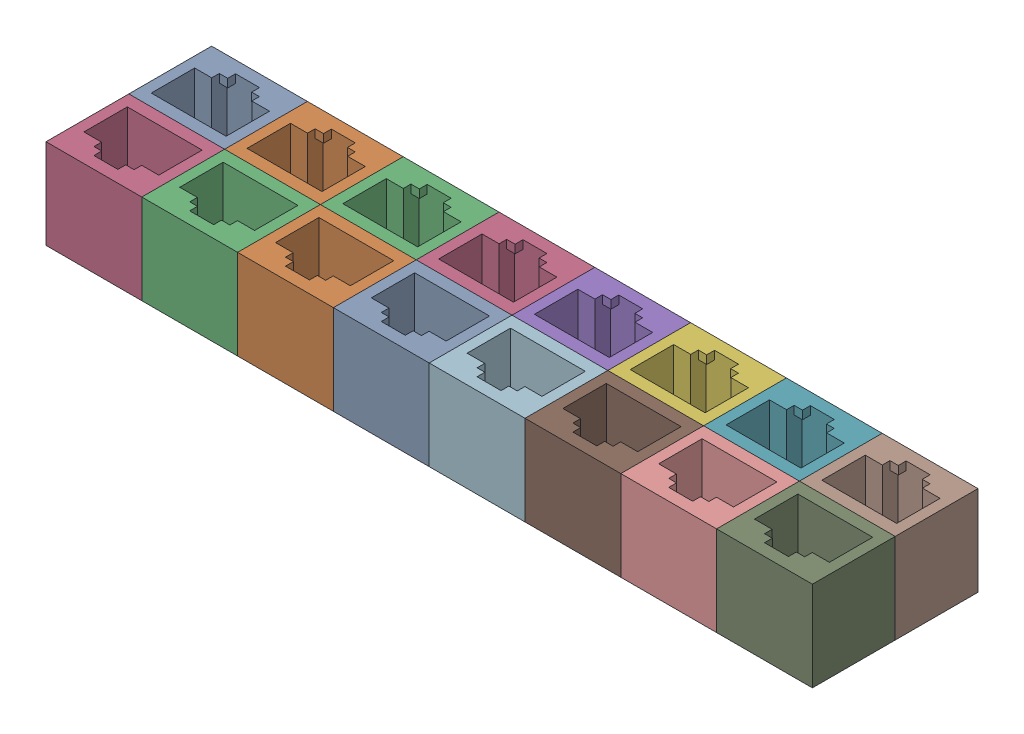
SolidWorks assembly 16-port block, configuration Default. Lengths in mm.
Overall size (128 15 27.66).
18 component instances, 1 part files, 3 mates.
Components (placement in the parent):
- 8-port block-1: 8-port block [Default] at (-9.936 3.3362 -7.2957) size (128 15 13.83)
  - RJ45 dummy jack trimmed-1: RJ45 dummy jack trimmed [Default] at (-39.7791 5.8279 33.2634) size (16 15 13.83)
  - RJ45 dummy jack trimmed-2: RJ45 dummy jack trimmed [Default] at (-23.7791 5.8279 33.2634) size (16 15 13.83)
  - RJ45 dummy jack trimmed-3: RJ45 dummy jack trimmed [Default] at (-7.7791 5.8279 33.2634) size (16 15 13.83)
  - RJ45 dummy jack trimmed-4: RJ45 dummy jack trimmed [Default] at (8.2209 5.8279 33.2634) size (16 15 13.83)
  - RJ45 dummy jack trimmed-5: RJ45 dummy jack trimmed [Default] at (24.2209 5.8279 33.2634) size (16 15 13.83)
  - RJ45 dummy jack trimmed-6: RJ45 dummy jack trimmed [Default] at (40.2209 5.8279 33.2634) size (16 15 13.83)
  - RJ45 dummy jack trimmed-7: RJ45 dummy jack trimmed [Default] at (56.2209 5.8279 33.2634) size (16 15 13.83)
  - RJ45 dummy jack trimmed-8: RJ45 dummy jack trimmed [Default] at (72.2209 5.8279 33.2634) size (16 15 13.83)
- 8-port block-3: 8-port block [Default] at (35.0058 3.3362 63.231) x (-1 0 0) z (0 0 -1) size (128 15 13.83)
  - RJ45 dummy jack trimmed-1: RJ45 dummy jack trimmed [Default] at (-39.7791 5.8279 33.2634) size (16 15 13.83)
  - RJ45 dummy jack trimmed-2: RJ45 dummy jack trimmed [Default] at (-23.7791 5.8279 33.2634) size (16 15 13.83)
  - RJ45 dummy jack trimmed-3: RJ45 dummy jack trimmed [Default] at (-7.7791 5.8279 33.2634) size (16 15 13.83)
  - RJ45 dummy jack trimmed-4: RJ45 dummy jack trimmed [Default] at (8.2209 5.8279 33.2634) size (16 15 13.83)
  - RJ45 dummy jack trimmed-5: RJ45 dummy jack trimmed [Default] at (24.2209 5.8279 33.2634) size (16 15 13.83)
  - RJ45 dummy jack trimmed-6: RJ45 dummy jack trimmed [Default] at (40.2209 5.8279 33.2634) size (16 15 13.83)
  - RJ45 dummy jack trimmed-7: RJ45 dummy jack trimmed [Default] at (56.2209 5.8279 33.2634) size (16 15 13.83)
  - RJ45 dummy jack trimmed-8: RJ45 dummy jack trimmed [Default] at (72.2209 5.8279 33.2634) size (16 15 13.83)
Mates (geometry in assembly coordinates):
- Coincident1: coincident: plane of 8-port block-1/RJ45 dummy jack trimmed-1 through (-51.4651 34.1641 27.9676) normal (0 0 1); plane of 8-port block-3/RJ45 dummy jack trimmed-8 through (-35.4651 34.1641 27.9676) normal (0 0 -1)
- Coincident2: coincident: point of assembly; point of assembly; moEndPointRef_w of 8-port block-1/RJ45 dummy jack trimmed-1; moEndPointRef_w of 8-port block-3/RJ45 dummy jack trimmed-8
- Coincident3: coincident: unknown of 8-port block-1/RJ45 dummy jack trimmed-1; unknown of 8-port block-3/RJ45 dummy jack trimmed-8
